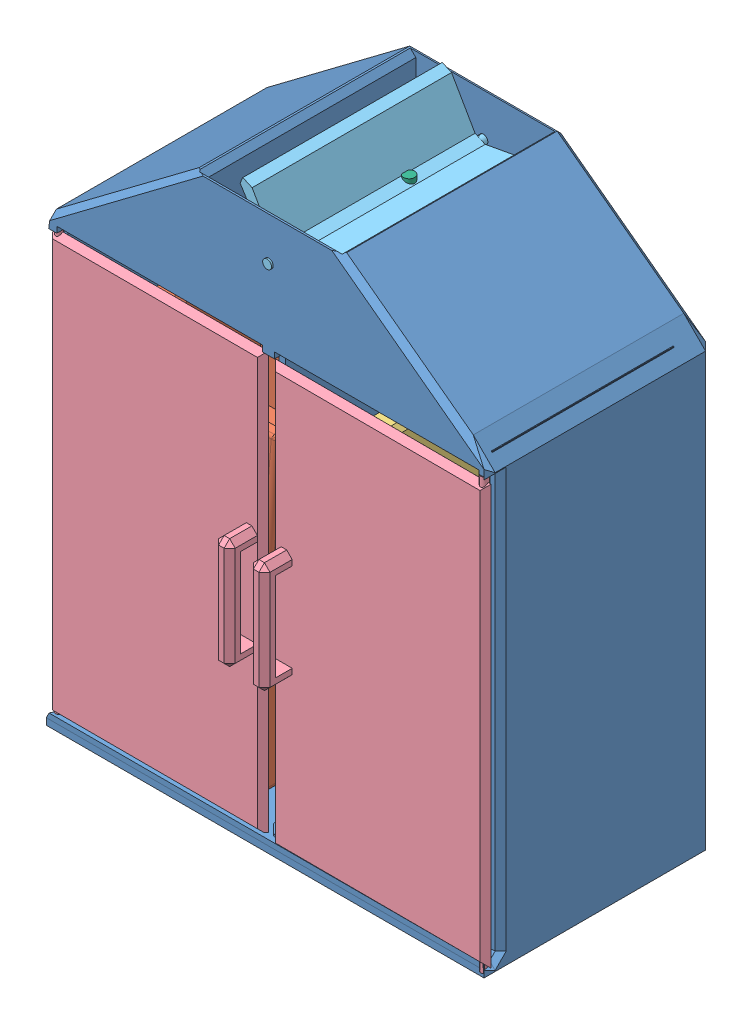
SolidWorks assembly 100%projek, configuration Default. Lengths in mm.
Overall size (800.16 1016.68 454.56).
7 component instances, 6 part files, 6 mates.
Components (placement in the parent):
- body utama 2-1: body utama 2 [Default] at (14.6988 125.3551 520.2396) size (800 1000 400.23)
- sampah 1-1: sampah 1 [Default] at (53.4831 716.3911 577.4637) x (1 0 0) z (0 -1 0) size (347.53 302.54 600)
- sampah 2 green-1: sampah 2 green [Default] at (451.7567 716.3911 574.9321) x (1 0 0) z (0 -1 0) size (347.53 350 600)
- pintu1-1: pintu1 [Default] at (-1.519 846.0354 898.7364) x (0.999999 0 0.001555) z (-0.001555 0 0.999999) size (390 776.8 70)
- pintu1-2: pintu1 [Default] at (714.6421 151.662 904.6774) x (-0.999995 0 -0.003055) z (-0.003055 0 0.999995) size (390 776.8 70)
- tutup sensor-2: tutup sensor [Default] at (371.0532 1050.7546 543.2728) x (0.91315 -0.407623 0) z (0 0 1) size (231 70 400)
- sensor-4: sensor [Default] at (350.7421 1010.7402 670.5486) x (0.997224 0.001469 -0.074442) z (-0.001474 0.999999 0) size (30 30 70)
Mates (geometry in assembly coordinates):
- Coincident1: coincident anti-aligned: plane of body utama 2-1 through (14.6988 125.3551 920.2396) normal (0 1 0); plane of sampah 1-1 through (35.5937 125.3551 877.4637) normal (0 -1 0)
- Coincident3: coincident anti-aligned: plane of body utama 2-1 through (14.6988 125.3551 920.2396) normal (0 1 0); plane of sampah 2 green-1 through (433.8672 125.3551 874.9321) normal (0 -1 0)
- Concentric4: concentric anti-aligned: circle of body utama 2-1; circle of pintu1-1
- Concentric5: concentric aligned: cylinder of body utama 2-1 through (743.3939 893.1243 915.2004) axis (0 -1 0) radius 5; cylinder of pintu1-2 through (743.3939 886.3899 915.2004) axis (0 -1 0) radius 6.631
- Concentric10: concentric anti-aligned: cylinder of body utama 2-1 through (359.3856 1026.514 309.7955) axis (0 0 1) radius 8.05; cylinder of tutup sensor-2 through (359.3856 1026.514 923.2728) axis (0 0 -1) radius 8.05
- Concentric13: concentric: cylinder of tutup sensor-2 through (361.3097 996.0017 668.722) axis (-0.001474 0.999999 0) radius 10; cylinder of sensor-4 through (361.2438 1040.7557 668.722) axis (0.001474 -0.999999 0) radius 10
